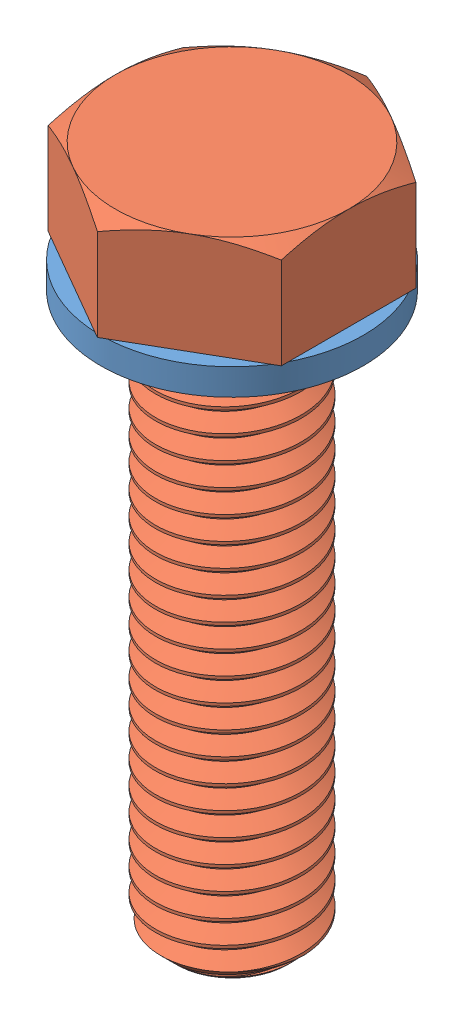
SolidWorks assembly ballscrew_carriabe_mount_screw, configuration Default. Lengths in mm.
Overall size (8 23.84 9.24).
2 component instances, 2 part files, 5 mates.
Components (placement in the parent):
- m5 washer 98689A114_General Purpose 18-8 Stainless Steel Washer-1: m5 washer 98689A114_General Purpose 18-8 Stainless Steel Washer [98689A114] at (0 0.5 0) x (1 0 0) z (0 -1 0) size (9 9 1) (hidden)
- m5-20mm hex bolt 91287A125_18-8 Stainless Steel Hex Head Screw-1: m5-20mm hex bolt 91287A125_18-8 Stainless Steel Hex Head Screw [91287A125] at (0 -7.25 0) x (1 0 0) z (0 1 0) size (8 9.24 23.84)
Mates (geometry in assembly coordinates):
- Concentric1: concentric anti-aligned: cylinder of m5 washer 98689A114_General Purpose 18-8 Stainless Steel Washer-1 through (0 0 0) axis (0 -1 0) radius 2.65
- Tangent1: tangent anti-aligned: torus of m5 washer 98689A114_General Purpose 18-8 Stainless Steel Washer-1
- Concentric2: concentric anti-aligned: cylinder of m5 washer 98689A114_General Purpose 18-8 Stainless Steel Washer-1 through (0 0 0) axis (0 -1 0) radius 2.65; circle of m5-20mm hex bolt 91287A125_18-8 Stainless Steel Hex Head Screw-1
- Coincident1: coincident anti-aligned: plane of m5 washer 98689A114_General Purpose 18-8 Stainless Steel Washer-1 through (0 1 2.65) normal (0 1 0); plane of m5-20mm hex bolt 91287A125_18-8 Stainless Steel Hex Head Screw-1 through (0 1 -4.6188) normal (0 -1 0)
- Parallel1: parallel anti-aligned: plane of m5-20mm hex bolt 91287A125_18-8 Stainless Steel Hex Head Screw-1 through (-4 -11.2202 -2.3094) normal (-1 0 0)
